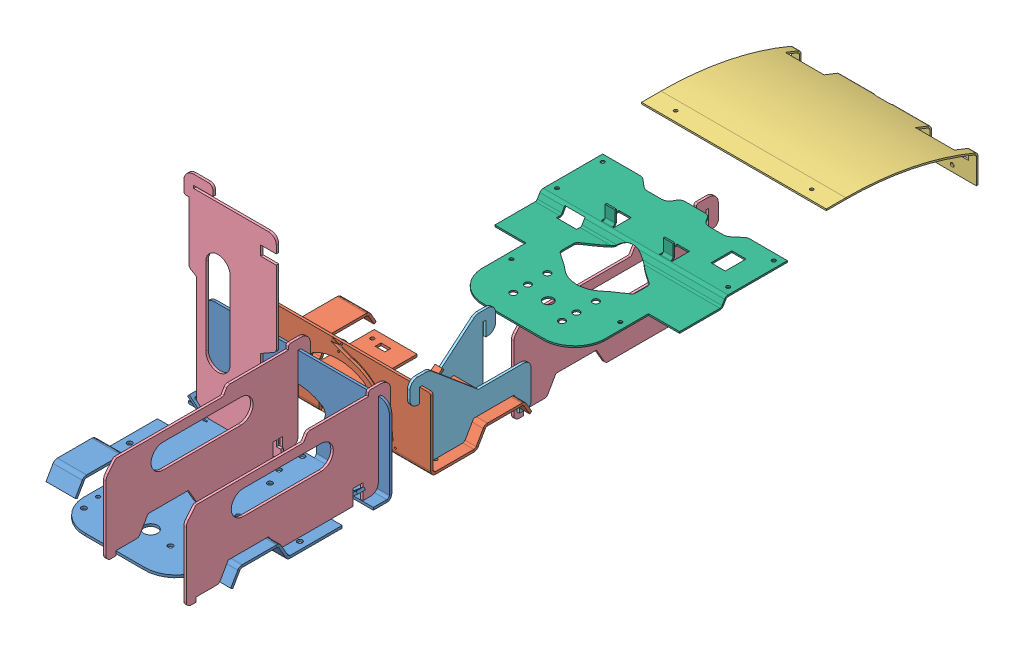
SolidWorks assembly TOOL, Design Assembly, configuration Default. Lengths in mm.
Overall size (120.65 190.26 509.93).
10 component instances, 6 part files, 24 mates.
Components (placement in the parent):
- CHASSIS, PLATE, REAR-1: CHASSIS, PLATE, REAR [Default] at origin size (120.65 55.58 120.66)
- CHASSIS, PLATE, FRONT-1: CHASSIS, PLATE, FRONT [DefaultSM-FLAT-PATTERN] at (0 0 -149.9886) size (120.65 47.32 66.05)
- CHASSIS, PLATE, HOOD-1: CHASSIS, PLATE, HOOD [DefaultSM-FLAT-PATTERN] at (0 -14.2737 -344.8701) size (120.65 35.99 99.06)
- TOOL, Rear Baseplate Checker-1: TOOL, Rear Baseplate Checker [Default] at origin size (1.6 63.27 133.51)
- TOOL, Rear Baseplate Checker-2: TOOL, Rear Baseplate Checker [Default] at (52.4002 0 0) size (1.6 63.27 133.51)
- TOOL, Rear Baseplate Checker-3: TOOL, Rear Baseplate Checker [Default] at (2.3114 67.599 -46.1619) x (0 0 1) z (0 -1 0) size (1.6 63.27 133.51)
- TOOL, Front Baseplate Checker-2: TOOL, Front Baseplate Checker [Default] at (52.4002 1.651 -143.6386) x (0 0 1) z (-1 0 0) size (79.15 53.75 1.6)
- TOOL, Front Baseplate Checker-3: TOOL, Front Baseplate Checker [Default] at (9.1758 -25.3492 -115.6606) x (0 0 -1) z (1 0 0) size (79.15 53.75 1.6)
- CHASSIS, PLATE, REAR COVER-1: CHASSIS, PLATE, REAR COVER [Default] at (0 0 -200.7886) size (120.65 14.86 118.69)
- TOOL, Rear Baseplate Checker-4: TOOL, Rear Baseplate Checker [Default] at (0 -53.8771 -266.4079) size (1.6 63.27 133.51)
Mates (geometry in assembly coordinates):
- Distance1: distance = 25.4 mm anti-aligned: plane of CHASSIS, PLATE, REAR-1 through (60.325 55.5752 -61.0886) normal (0 0 -1); plane of CHASSIS, PLATE, FRONT-1 through (-60.325 47.3202 -86.4886) normal (0 0 1)
- Coincident2: coincident aligned: plane of CHASSIS, PLATE, REAR-1 through (0 0 0) normal (1 0 0); plane of CHASSIS, PLATE, FRONT-1 through (0 0 -149.9886) normal (1 0 0)
- Coincident3: coincident aligned: plane of CHASSIS, PLATE, REAR-1 through (-40.005 1.6002 6.2214) normal (0 1 0); plane of CHASSIS, PLATE, FRONT-1 through (-40.005 1.6002 -115.6986) normal (0 1 0)
- Coincident8: coincident aligned: plane of CHASSIS, PLATE, REAR-1 through (0 0 0) normal (1 0 0); plane of assembly through (0 0 0) normal (1 0 0)
- Coincident9: coincident aligned: plane of CHASSIS, PLATE, REAR-1 through (0 0 0) normal (0 0 1); plane of assembly through (0 0 0) normal (0 0 1)
- Coincident10: coincident aligned: plane of CHASSIS, PLATE, REAR-1 through (0 0 0) normal (0 1 0); plane of assembly through (0 0 0) normal (0 1 0)
- Coincident11: coincident aligned: plane of CHASSIS, PLATE, HOOD-1 through (0 -14.2737 -344.8701) normal (1 0 0); plane of assembly through (0 0 0) normal (1 0 0)
- Concentric1: concentric aligned: cylinder of TOOL, Rear Baseplate Checker-1 through (0.8001 39.7764 -22.1067) axis (-1 0 0) radius 7.9375; cylinder of TOOL, Rear Baseplate Checker-2 through (53.2003 39.7764 -22.1067) axis (-1 0 0) radius 7.9375
- Concentric2: concentric aligned: cylinder of TOOL, Rear Baseplate Checker-1 through (0.8001 39.7764 28.6933) axis (-1 0 0) radius 7.9375; cylinder of TOOL, Rear Baseplate Checker-2 through (53.2003 39.7764 28.6933) axis (-1 0 0) radius 7.9375
- Distance4: distance = 50.8 mm anti-aligned: plane of TOOL, Rear Baseplate Checker-1 through (0.8001 1.905 62.8238) normal (1 0 0); plane of TOOL, Rear Baseplate Checker-2 through (51.6001 1.905 62.8238) normal (-1 0 0)
- Coincident15: coincident anti-aligned: plane of CHASSIS, PLATE, REAR-1 through (-40.005 1.6002 6.2214) normal (0 1 0); plane of TOOL, Rear Baseplate Checker-3 through (0.4064 1.6002 -45.3618) normal (0 -1 0)
- Coincident17: coincident anti-aligned: plane of CHASSIS, PLATE, REAR-1 through (-43.815 1.6002 -43.6219) normal (0.642788 0.766044 0); plane of TOOL, Rear Baseplate Checker-3 through (-45.2314 2.7887 -45.3618) normal (-0.642788 -0.766044 0)
- Width1: width: plane of CHASSIS, PLATE, REAR-1 through (-55.5452 9.3541 -43.6219) normal (0 0 1); plane of CHASSIS, PLATE, REAR-1 through (-44.8436 0.3744 -48.7019) normal (0 0 -1); plane of TOOL, Rear Baseplate Checker-3 through (0.4064 4.7752 -46.962) normal (0 0 -1); plane of TOOL, Rear Baseplate Checker-3 through (0.4064 4.7752 -45.3618) normal (0 0 1)
- Coincident21: coincident aligned: plane of TOOL, Rear Baseplate Checker-2 through (53.2003 1.905 62.8238) normal (1 0 0); plane of TOOL, Front Baseplate Checker-2 through (53.2003 3.175 -156.034) normal (1 0 0)
- Width2: width: plane of CHASSIS, PLATE, FRONT-1 through (11.557 0.3744 -135.1081) normal (1 0 0); plane of CHASSIS, PLATE, FRONT-1 through (6.7945 7.7214 -143.864) normal (-1 0 0); plane of TOOL, Front Baseplate Checker-3 through (8.3757 -23.8252 -103.2652) normal (-1 0 0); plane of TOOL, Front Baseplate Checker-3 through (9.9758 -23.8252 -103.2652) normal (1 0 0)
- Coincident23: coincident anti-aligned: plane of CHASSIS, PLATE, FRONT-1 through (11.557 0.3744 -135.1081) normal (0 -0.766044 -0.642788); plane of TOOL, Front Baseplate Checker-3 through (9.9758 0 -134.6619) normal (0 0.766044 0.642788)
- Coincident24: coincident anti-aligned: plane of CHASSIS, PLATE, FRONT-1 through (-40.005 0 -115.6986) normal (0 -1 0); plane of TOOL, Front Baseplate Checker-3 through (9.9758 0 -105.1702) normal (0 1 0)
- Coincident25: coincident aligned: plane of CHASSIS, PLATE, REAR-1 through (0 0 0) normal (1 0 0); plane of CHASSIS, PLATE, REAR COVER-1 through (0 0 -200.7886) normal (1 0 0)
- Coincident26: coincident aligned: plane of CHASSIS, PLATE, FRONT-1 through (-40.005 0 -115.6986) normal (0 -1 0); plane of CHASSIS, PLATE, REAR COVER-1 through (-19.724 0 -221.0974) normal (0 -1 0)
- Distance5: distance = 50.8 mm anti-aligned: plane of CHASSIS, PLATE, REAR COVER-1 through (19.05 1.016 -200.7886) normal (0 0 1); plane of CHASSIS, PLATE, FRONT-1 through (40.005 1.6002 -149.9886) normal (0 0 -1)
- Distance6: distance = 25.4 mm anti-aligned: plane of CHASSIS, PLATE, REAR COVER-1 through (60.325 5.9653 -319.4701) normal (0 0 -1); plane of CHASSIS, PLATE, HOOD-1 through (60.325 21.4641 -344.8701) normal (0 0 1)
- Coincident27: coincident aligned: plane of CHASSIS, PLATE, REAR COVER-1 through (0 0 -200.7886) normal (1 0 0); plane of TOOL, Rear Baseplate Checker-4 through (0 -53.8771 -266.4079) normal (1 0 0)
- Distance8: distance = 3.175 mm anti-aligned: plane of CHASSIS, PLATE, REAR COVER-1 through (60.325 4.9493 -279.7977) normal (0 -1 0); plane of TOOL, Rear Baseplate Checker-4 through (0.8001 8.1243 -327.5727) normal (0 1 0)
- Distance7: distance = 6.35 mm aligned: plane of TOOL, Rear Baseplate Checker-4 through (0.8001 -47.1207 -325.8201) normal (0 0 -1); plane of CHASSIS, PLATE, REAR COVER-1 through (60.325 5.9653 -319.4701) normal (0 0 -1); sketch_entity of ?
